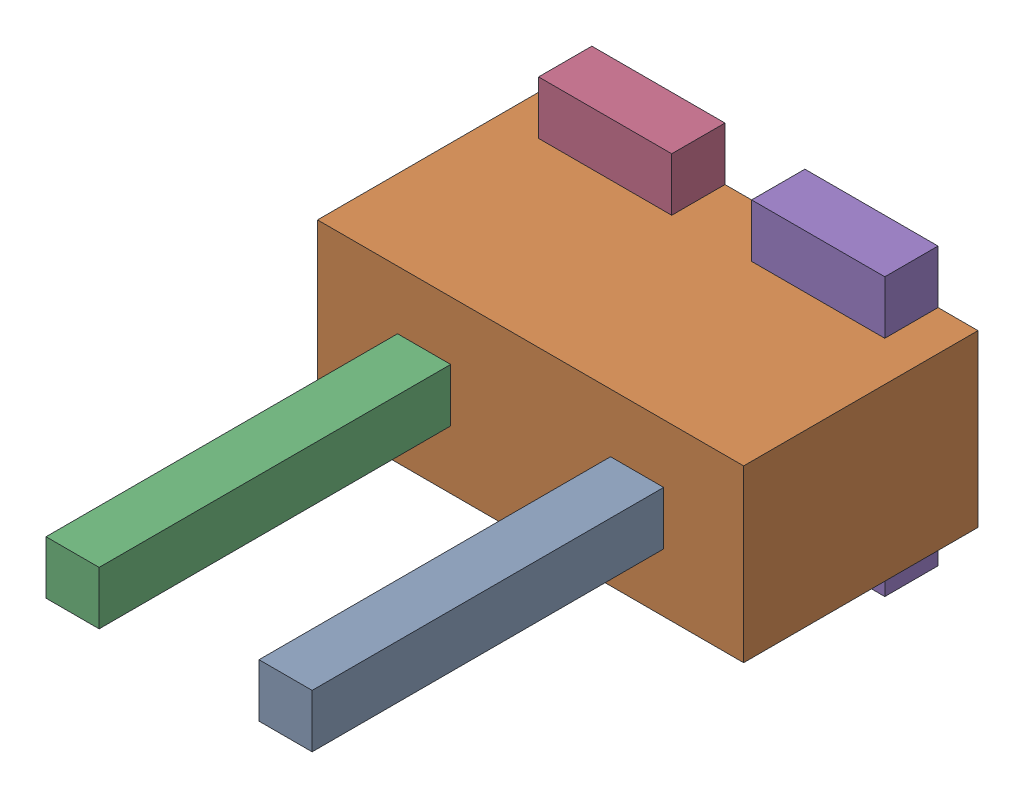
SolidWorks assembly J14, configuration ﾃﾞﾌｫﾙﾄ. Lengths in mm.
Overall size (4 2.6 5.5).
10 component instances, 3 part files, 0 mates.
Components (placement in the parent):
- 689260424-1: 689260424 [ﾃﾞﾌｫﾙﾄ] at (7.5001 67 2.2) size (0.5 0.5 3.3)
  - Extruded_23-1: Extruded_23 [ﾃﾞﾌｫﾙﾄ] at origin size (0.5 0.5 3.3)
- 689260560-1: 689260560 [ﾃﾞﾌｫﾙﾄ] at (6.5 67 0) size (4 1.6 2.2)
  - Extruded_24-1: Extruded_24 [ﾃﾞﾌｫﾙﾄ] at origin size (4 1.6 2.2)
- 689260424-2: 689260424 [ﾃﾞﾌｫﾙﾄ] at (5.5006 67 2.2) size (0.5 0.5 3.3)
  - Extruded_23-1: Extruded_23 [ﾃﾞﾌｫﾙﾄ] at origin size (0.5 0.5 3.3)
- 689260696-1: 689260696 [ﾃﾞﾌｫﾙﾄ] at (5.5001 67.0001 0) size (1.25 2.6 0.5)
  - Extruded_25-1: Extruded_25 [ﾃﾞﾌｫﾙﾄ] at origin size (1.25 2.6 0.5)
- 689260696-2: 689260696 [ﾃﾞﾌｫﾙﾄ] at (7.5001 67.0001 0) size (1.25 2.6 0.5)
  - Extruded_25-1: Extruded_25 [ﾃﾞﾌｫﾙﾄ] at origin size (1.25 2.6 0.5)
